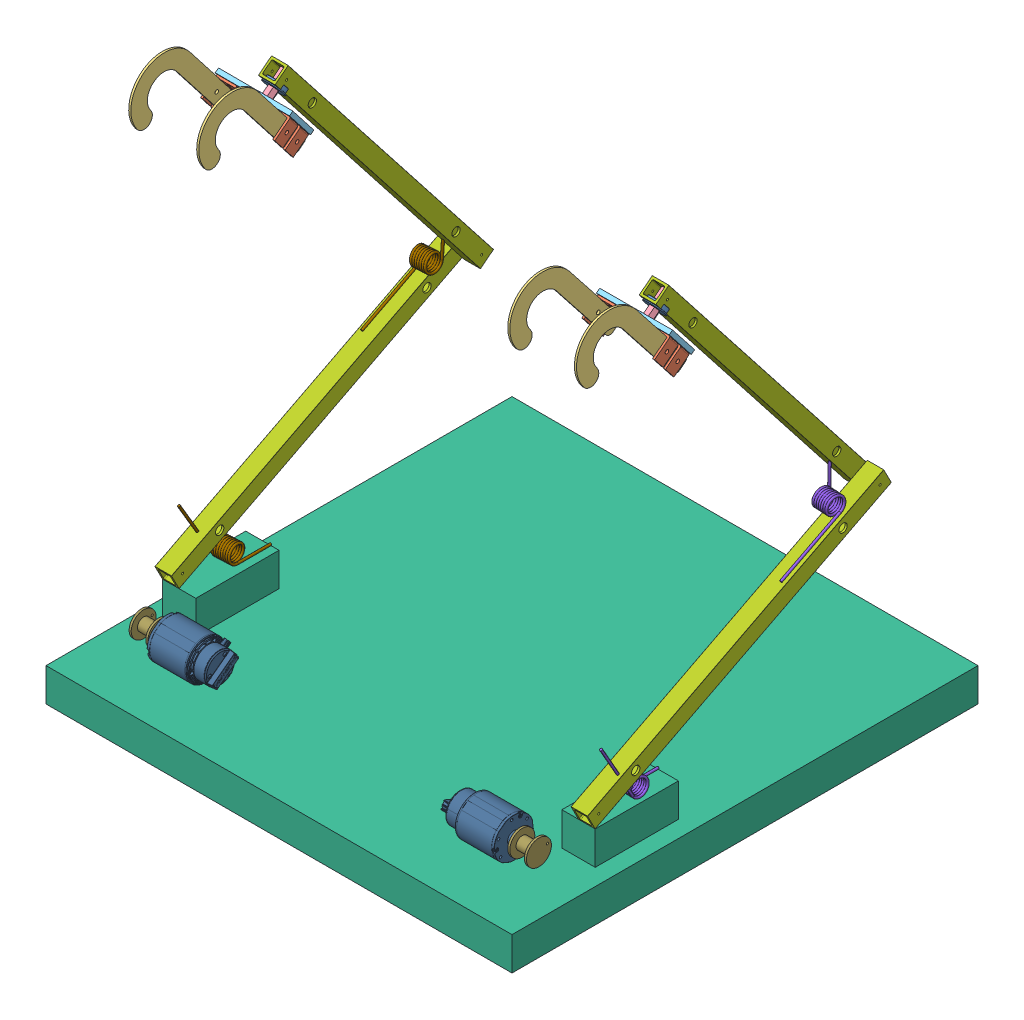
SolidWorks assembly new climber design prototype, configuration Default. Lengths in mm.
Overall size (711.2 808.4 711.2).
37 component instances, 12 part files, 49 mates.
Components (placement in the parent):
- half in hex bearing for clibmer-1: half in hex bearing for clibmer [Default] at (1873.9135 1723.5322 1864.973) x (-1 0 0) z (0 0.616865 -0.787069) size (31.12 31.12 7.93)
- Bracket for climber prototype-3: Bracket for climber prototype [Default] at (1914.1787 1741.449 1881.0322) x (0.999875 0.012453 0.00976) z (0.015822 -0.786971 -0.616788) size (30.99 30.99 20.57)
- Bracket for climber prototype-4: Bracket for climber prototype [Default] at (1833.6484 1703.6569 1851.4127) x (-0.999875 -0.012453 -0.00976) z (-0.015822 0.786971 0.616788) size (30.99 30.99 20.57)
- Bracket for climber prototype-5: Bracket for climber prototype [Default] at (1914.5927 1720.8603 1864.8958) x (0.999875 0.012453 0.00976) z (0.015822 -0.786971 -0.616788) size (30.99 30.99 20.57)
- Bracket for climber prototype-6: Bracket for climber prototype [Default] at (1833.2344 1724.2457 1867.5491) x (-0.999875 -0.012453 -0.00976) z (-0.015822 0.786971 0.616788) size (30.99 30.99 20.57)
- Candy cane claw-1: Candy cane claw [Default] at (1924.1548 1688.5765 1863.3643) x (0 0.616865 -0.787069) z (0.999875 0.012453 0.00976) size (101.6 177.8 3.17)
- Candy cane claw-2: Candy cane claw [Default] at (1821.4247 1687.297 1862.3615) x (0 0.616865 -0.787069) z (0.999875 0.012453 0.00976) size (101.6 177.8 3.17)
- shortHex shaft for climber-1: shortHex shaft for climber [Default] at (1873.9135 1752.9104 1827.4888) x (0 -0.616865 0.787069) z (-1 0 0) size (48.3 12.7 14.66)
- half in hex bearing for clibmer-2: half in hex bearing for clibmer [Default] at (1873.9135 1741.192 1842.4405) x (0.560177 -0.651987 -0.510994) z (0 -0.616865 0.787069) size (31.12 31.12 7.93)
- wood piece for pivot in climber-1: wood piece for pivot in climber [Default] at (1873.9135 1727.4493 1859.9751) x (0 -0.616865 0.787069) z (0.999875 0.012453 0.00976) size (6.35 53.34 112.27)
- chasis box for climber prototype-1: chasis box for climber prototype [Default] at (1583.147 1030.9002 1775.5006) size (711.2 101.6 711.2)
- 1x1x20 box extrusion for climber-1: 1x1x20 box extrusion for climber [Default] at (1887.947 1364.3467 1526.6927) x (1 0 0) z (0 -0.456391 0.889779) size (25.4 25.4 508)
- 1x1x20 box extrusion for climber-2: 1x1x20 box extrusion for climber [Default] at (1860.9595 1767.9041 1839.2401) x (1 0 0) z (0 -0.787069 -0.616865) size (25.4 25.4 508)
- 1x1x20 box extrusion for climber-3: 1x1x20 box extrusion for climber [Default] at (1305.3345 1368.0729 1525.8728) x (-1 0 0) z (0 0.787069 0.616865) size (25.4 25.4 508)
- Candy cane claw-3: Candy cane claw [Default] at (1341.6948 1687.3365 1862.3925) x (0 0.616865 -0.787069) z (0.999875 -0.012453 -0.00976) size (101.6 177.8 3.17)
- Candy cane claw-4: Candy cane claw [Default] at (1238.9646 1688.616 1863.3953) x (0 0.616865 -0.787069) z (0.999875 -0.012453 -0.00976) size (101.6 177.8 3.17)
- Bracket for climber prototype-7: Bracket for climber prototype [Default] at (1333.3852 1740.4368 1880.2389) x (0.999875 -0.012453 -0.00976) z (-0.015822 -0.786971 -0.616788) size (30.99 30.99 20.57)
- Bracket for climber prototype-8: Bracket for climber prototype [Default] at (1332.9712 1719.8481 1864.1025) x (0.999875 -0.012453 -0.00976) z (-0.015822 -0.786971 -0.616788) size (30.99 30.99 20.57)
- half in hex bearing for clibmer-3: half in hex bearing for clibmer [Default] at (1292.3805 1741.192 1842.4405) x (-0.560177 -0.651987 -0.510994) z (0 -0.616865 0.787069) size (31.12 31.12 7.93)
- shortHex shaft for climber-2: shortHex shaft for climber [Default] at (1292.3805 1752.9104 1827.4888) x (0 -0.616865 0.787069) z (1 0 0) size (48.3 12.7 14.66)
- Bracket for climber prototype-9: Bracket for climber prototype [Default] at (1251.3759 1704.6691 1852.206) x (-0.999875 0.012453 0.00976) z (0.015822 0.786971 0.616788) size (30.99 30.99 20.57)
- Bracket for climber prototype-10: Bracket for climber prototype [Default] at (1251.7898 1725.2579 1868.3424) x (-0.999875 0.012453 0.00976) z (0.015822 0.786971 0.616788) size (30.99 30.99 20.57)
- half in hex bearing for clibmer-4: half in hex bearing for clibmer [Default] at (1292.3805 1723.5322 1864.973) x (1 0 0) z (0 0.616865 -0.787069) size (31.12 31.12 7.93)
- wood piece for pivot in climber-2: wood piece for pivot in climber [Default] at (1292.3805 1727.4493 1859.9751) x (0 -0.616865 0.787069) z (0.999875 -0.012453 -0.00976) size (6.35 53.34 112.27)
- 1x1x20 box extrusion for climber-4: 1x1x20 box extrusion for climber [Default] at (1278.347 1132.5002 1978.7006) x (-1 0 0) z (0 0.456391 -0.889779) size (25.4 25.4 508)
- shortHex shaft for climber-3: shortHex shaft for climber [Default] at (1864.1345 1370.0779 1543.9027) x (1 0 0) z (0 0.989584 -0.143953) size (48.3 12.7 14.66)
- shortHex shaft for climber-4: shortHex shaft for climber [Default] at (1302.1595 1370.0779 1543.9027) x (-1 0 0) z (0 0.989584 -0.143953) size (48.3 12.7 14.66)
- left Torsion Spring-1: left Torsion Spring [9271K643] at (1906.997 1368.7634 1604.4011) x (0.998999 -0.020411 0.039793) z (-0.044723 -0.455934 0.888889) size (35 52.69 139.07)
- Torsion Spring for climber-3: Torsion Spring for climber [9271K706] at (1259.297 1372.9277 1596.2825) x (0.998999 0.020411 -0.039793) z (0.044723 -0.455934 0.888889) size (35 52.69 139.07)
- Torsion Spring for climber-4: Torsion Spring for climber [9271K706] at (1266.2067 1146.4956 1903.6078) x (0.998999 0 -0.044723) z (0.022361 0.866025 0.4995) size (35 52.69 139.07)
- left Torsion Spring-4: left Torsion Spring [9271K643] at (1906.8216 1146.4956 1903.6078) x (0.998999 0 0.044723) z (-0.022361 0.866025 0.4995) size (35 52.69 139.07)
- Falcon 500-1: Falcon 500 [Default] at (1787.2473 1117.4901 2037.573) x (0 0.126991 -0.991904) z (1 0 0) size (62.05 60 125.3)
- hex adapter for falcon-1: hex adapter for falcon [Default] at (1857.7845 1117.4901 2037.573) x (0 0.126991 -0.991904) z (1 0 0) size (14.66 12.7 25.4)
- spool for cord on climber-1: spool for cord on climber [Default] at (1857.7845 1117.4901 2037.573) x (0 -0.930491 -0.366314) z (1 0 0) size (38.1 38.1 28.57)
- spool for cord on climber-2: spool for cord on climber [Default] at (1308.5095 1117.4901 2037.573) x (0 0.930491 0.366314) z (-1 0 0) size (38.1 38.1 28.57)
- Falcon 500-2: Falcon 500 [Default] at (1379.0468 1117.4901 2037.573) x (0 0.126991 -0.991904) z (-1 0 0) size (62.05 60 125.3)
- hex adapter for falcon-2: hex adapter for falcon [Default] at (1283.1095 1117.4901 2037.573) x (0 0.126991 -0.991904) z (1 0 0) size (14.66 12.7 25.4)
Mates (geometry in assembly coordinates):
- Concentric12: concentric anti-aligned: cylinder of Bracket for climber prototype-5 through (1899.2634 1703.9933 1869.3451) axis (0.999875 0.012453 0.00976) radius 2.667; cylinder of Candy cane claw-1 through (1927.0729 1704.3397 1869.6165) axis (-0.999875 -0.012453 -0.00976) radius 2.794
- Parallel10: parallel anti-aligned: cylinder of Bracket for climber prototype-3 through (1898.8494 1724.582 1885.4815) axis (0.999875 0.012453 0.00976) radius 2.667; cylinder of Candy cane claw-1 through (1926.6589 1724.9284 1885.7529) axis (-0.999875 -0.012453 -0.00976) radius 2.794
- Coincident15: coincident anti-aligned: plane of Bracket for climber prototype-3 through (1926.8217 1724.432 1869.7121) normal (-0.999875 -0.012453 -0.00976); plane of Candy cane claw-1 through (1925.32 1767.9854 1967.9805) normal (0.999875 0.012453 0.00976)
- Concentric14: concentric anti-aligned: cylinder of Bracket for climber prototype-3 through (1898.8494 1724.582 1885.4815) axis (0.999875 0.012453 0.00976) radius 2.667; cylinder of Candy cane claw-1 through (1926.6589 1724.9284 1885.7529) axis (-0.999875 -0.012453 -0.00976) radius 2.794
- Concentric15: concentric aligned: cylinder of Bracket for climber prototype-6 through (1848.5637 1723.9557 1884.9906) axis (-0.999875 -0.012453 -0.00976) radius 2.667; cylinder of Candy cane claw-2 through (1823.9288 1723.6489 1884.7501) axis (-0.999875 -0.012453 -0.00976) radius 2.794
- Concentric16: concentric aligned: cylinder of Bracket for climber prototype-4 through (1848.9777 1703.367 1868.8542) axis (-0.999875 -0.012453 -0.00976) radius 2.667; cylinder of Candy cane claw-2 through (1824.3427 1703.0602 1868.6137) axis (-0.999875 -0.012453 -0.00976) radius 2.794
- Coincident16: coincident anti-aligned: plane of Bracket for climber prototype-6 through (1820.5914 1739.3041 1881.3681) normal (0.999875 0.012453 0.00976); plane of Candy cane claw-2 through (1819.4153 1766.6664 1966.9467) normal (-0.999875 -0.012453 -0.00976)
- Concentric18: concentric aligned: circle of Hex shaft for climber-1; circle of wood piece for pivot in climber-1
- Coincident23: coincident aligned: plane of shortHex shaft for climber-1 through (1873.9135 1723.5322 1864.973) normal (0 -0.616865 0.787069); plane of wood piece for pivot in climber-1 through (1873.9135 1723.5322 1864.973) normal (0 -0.616865 0.787069)
- Concentric21: concentric aligned: circle of half in hex bearing for clibmer-1; circle of Hex shaft for climber-1
- Coincident32: coincident aligned: plane of half in hex bearing for clibmer-1 through (1873.9135 1723.5322 1864.973) normal (0 -0.616865 0.787069); plane of wood piece for pivot in climber-1 through (1873.9135 1723.5322 1864.973) normal (0 -0.616865 0.787069)
- Parallel15: parallel anti-aligned: line of Bracket for climber prototype-3 through (1899.0122 1726.0442 1866.9417) axis (0.999875 0.012453 0.00976); line of Bracket for climber prototype-6 through (1848.7265 1725.4179 1866.4509) axis (-0.999875 -0.012453 -0.00976)
- Parallel16: parallel anti-aligned: line of Bracket for climber prototype-4 through (1848.8149 1721.0203 1863.0043) axis (-0.999875 -0.012453 -0.00976); line of Bracket for climber prototype-5 through (1899.1006 1721.6466 1863.4951) axis (0.999875 0.012453 0.00976)
- Coincident38: coincident anti-aligned: plane of Bracket for climber prototype-5 through (1927.2356 1703.8433 1853.5757) normal (-0.999875 -0.012453 -0.00976); plane of Candy cane claw-1 through (1925.32 1767.9854 1967.9805) normal (0.999875 0.012453 0.00976)
- Concentric23: concentric aligned: cylinder of Bracket for climber prototype-3 through (1914.3415 1715.2173 1897.8275) axis (0 0.616865 -0.787069) radius 2.794; cylinder of wood piece for pivot in climber-1 through (1914.3415 1734.3327 1873.4378) axis (0 0.616865 -0.787069) radius 3.175
- Concentric24: concentric aligned: cylinder of Bracket for climber prototype-5 through (1914.7554 1694.6286 1881.6912) axis (0 0.616865 -0.787069) radius 2.794; cylinder of wood piece for pivot in climber-1 through (1914.7554 1713.744 1857.3015) axis (0 0.616865 -0.787069) radius 3.175
- Concentric25: concentric aligned: cylinder of Bracket for climber prototype-6 through (1833.0717 1714.2051 1897.0342) axis (0 0.616865 -0.787069) radius 2.794; cylinder of wood piece for pivot in climber-1 through (1833.0717 1733.3205 1872.6445) axis (0 0.616865 -0.787069) radius 3.175
- Concentric26: concentric aligned: cylinder of Bracket for climber prototype-4 through (1833.4856 1693.6164 1880.8978) axis (0 0.616865 -0.787069) radius 2.794; cylinder of wood piece for pivot in climber-1 through (1833.4856 1712.7318 1856.5081) axis (0 0.616865 -0.787069) radius 3.175
- Coincident40: coincident anti-aligned: plane of Bracket for climber prototype-6 through (1817.4168 1741.2231 1878.8382) normal (0 0.616865 -0.787069); plane of wood piece for pivot in climber-1 through (1873.9135 1723.5322 1864.973) normal (0 -0.616865 0.787069)
- Coincident41: coincident anti-aligned: plane of Bracket for climber prototype-3 through (1929.9963 1726.4301 1867.2442) normal (0 0.616865 -0.787069); plane of wood piece for pivot in climber-1 through (1873.9135 1723.5322 1864.973) normal (0 -0.616865 0.787069)
- Parallel18: parallel anti-aligned: plane of half in hex bearing for clibmer-1 through (1881.2459 1728.4223 1858.7336) normal (-0.866025 -0.393535 -0.308432); plane of shortHex shaft for climber-1 through (1881.2459 1723.5322 1864.973) normal (0.866025 0.393535 0.308432)
- Coincident42: coincident aligned: line of chasis box for climber prototype-1 through (1913.347 1132.5002 1978.7006) axis (-1 0 0); line of 1x1x20 box extrusion for climber-1 through (1913.093 1132.5002 1978.7006) axis (-1 0 0)
- Coincident43: coincident aligned: plane of chasis box for climber prototype-1 through (1913.347 1132.5002 1978.7006) normal (1 0 0); plane of 1x1x20 box extrusion for climber-1 through (1913.347 1154.8746 1990.177) normal (1 0 0)
- Concentric27: concentric anti-aligned: circle of Hex shaft for climber-1; circle of half in hex bearing for clibmer-2
- Coincident49: coincident aligned: plane of shortHex shaft for climber-1 through (1873.9135 1752.9104 1827.4888) normal (0 0.616865 -0.787069); plane of 1x1x20 box extrusion for climber-2 through (1886.1055 1368.0729 1525.8728) normal (0 0.616865 -0.787069)
- Distance1: distance = 12.7 mm aligned: plane of shortHex shaft for climber-1 through (1877.5797 1728.5301 1868.8901) normal (0 0.787069 0.616865); plane of 1x1x20 box extrusion for climber-2 through (1861.2135 1767.7474 1839.44) normal (0 0.787069 0.616865)
- Distance2: distance = 12.7 mm: point of shortHex shaft for climber-1; line of 1x1x20 box extrusion for climber-2 through (1861.2135 1368.0729 1525.8728) axis (0 0.787069 0.616865)
- Coincident52: coincident anti-aligned: plane of half in hex bearing for clibmer-2 through (1881.7392 1728.1338 1840.3418) normal (0 0.616865 -0.787069); plane of 1x1x20 box extrusion for climber-2 through (1861.2135 1352.4046 1545.8644) normal (0 -0.616865 0.787069)
- Concentric29: concentric anti-aligned: circle of 1x1x18 box extrusion for climber-1; circle of shortHex shaft for climber-3
- Concentric32: concentric anti-aligned: circle of 1x1x18 box extrusion for climber-2; circle of shortHex shaft for climber-3
- Distance8: distance = 1.5875 mm anti-aligned: plane of 1x1x20 box extrusion for climber-2 through (1886.3595 1352.5613 1545.6644) normal (1 0 0); plane of 1x1x20 box extrusion for climber-1 through (1887.947 1132.7262 1978.8166) normal (-1 0 0)
- Coincident62: coincident anti-aligned: plane of 1x1x20 box extrusion for climber-2 through (1864.1345 1355.3424 1542.1159) normal (1 0 0); plane of shortHex shaft for climber-3 through (1864.1345 1370.0779 1543.9027) normal (-1 0 0)
- Tangent7: tangent anti-aligned: plane of 1x1x20 box extrusion for climber-1 through (1888.201 1155.1006 1990.293) normal (0 0.889779 0.456391); cylinder of left Torsion Spring-1 through (1906.997 1311.4669 1689.1978) axis (0 0.456391 -0.889779) radius 1.7145
- Distance9: distance = 6.35 mm: plane of 1x1x20 box extrusion for climber-1 through (1913.347 1154.8746 1990.177) normal (1 0 0); cylinder of left Torsion Spring-1 through (1906.997 1311.4669 1689.1978) axis (0 0.456391 -0.889779) radius 1.7145
- Tangent12: tangent anti-aligned: plane of 1x1x20 box extrusion for climber-1 through (1888.201 1155.1006 1990.293) normal (0 0.889779 0.456391); face of left Torsion Spring-1
- Distance14: distance = 6.35 mm: cylinder of Torsion Spring for climber-3 through (1259.297 1315.6311 1681.0792) axis (0 0.456391 -0.889779) radius 1.7145; plane of 1x1x20 box extrusion for climber-4 through (1252.947 1386.721 1538.1691) normal (-1 0 0)
- Tangent19: tangent anti-aligned: plane of 1x1x20 box extrusion for climber-4 through (1278.093 1386.9471 1538.285) normal (0 0.889779 0.456391); cylinder of Torsion Spring for climber-3 through (1259.297 1315.6311 1681.0792) axis (0 0.456391 -0.889779) radius 1.7145
- Tangent20: tangent anti-aligned: plane of 1x1x20 box extrusion for climber-4 through (1278.093 1386.9471 1538.285) normal (0 0.889779 0.456391); edge_curve of Torsion Spring for climber-3
- Coincident69: coincident aligned: plane of chasis box for climber prototype-1 through (1252.947 1132.5002 1851.7006) normal (0 0 -1); circle of Torsion Spring for climber-4
- Tangent24: tangent anti-aligned: plane of chasis box for climber prototype-1 through (1583.147 1132.5002 1775.5006) normal (0 1 0); cylinder of Torsion Spring for climber-4 through (1290.9385 1134.2147 1851.7006) axis (0 0 1) radius 1.7145
- Tangent25: tangent anti-aligned: plane of chasis box for climber prototype-1 through (1583.147 1132.5002 1775.5006) normal (0 1 0); edge_curve of Torsion Spring for climber-4
- Coincident70: coincident aligned: plane of chasis box for climber prototype-1 through (1913.347 1132.5002 1851.7006) normal (0 0 -1); circle of left Torsion Spring-4
- Tangent26: tangent anti-aligned: plane of chasis box for climber prototype-1 through (1583.147 1132.5002 1775.5006) normal (0 1 0); cylinder of left Torsion Spring-4 through (1882.0898 1134.2147 1851.7006) axis (0 0 1) radius 1.7145
- Tangent27: tangent anti-aligned: plane of chasis box for climber prototype-1 through (1583.147 1132.5002 1775.5006) normal (0 1 0); edge_curve of left Torsion Spring-4
- Concentric33: concentric anti-aligned: circle of Falcon 500-1; circle of hex adapter for falcon-1
- Concentric34: concentric anti-aligned: circle of hex adapter for falcon-1; circle of spool for cord on climber-1
- Coincident72: coincident aligned: plane of hex adapter for falcon-1 through (1857.7845 1117.4901 2037.573) normal (-1 0 0); plane of spool for cord on climber-1 through (1857.7845 1117.4901 2037.573) normal (-1 0 0)
- Coincident75: coincident aligned: plane of Falcon 500-1 through (1883.1845 1120.0395 2036.0245) normal (1 0 0); plane of hex adapter for falcon-1 through (1883.1845 1117.4901 2037.573) normal (1 0 0)
- Coincident77: coincident aligned: plane of 1x1x20 box extrusion for climber-2 through (1886.3595 1352.5613 1545.6644) normal (1 0 0); plane of spool for cord on climber-1 through (1886.3595 1117.4901 2037.573) normal (1 0 0)
